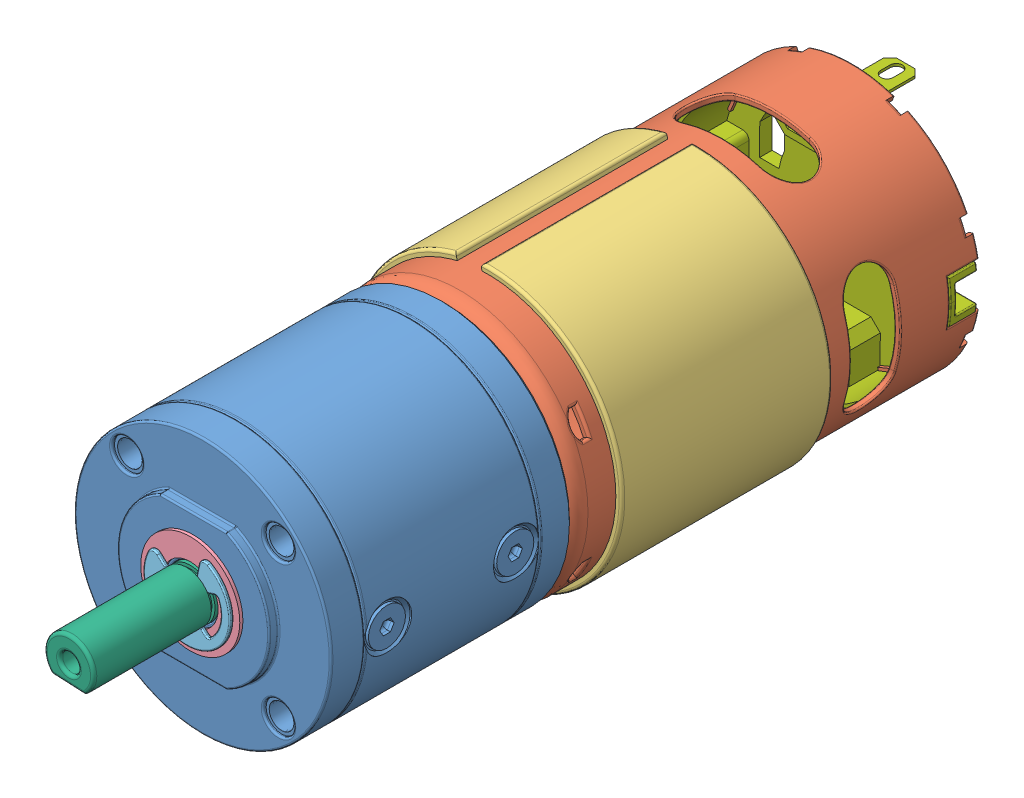
SolidWorks assembly motorDC, configuration Default. Lengths in mm.
Overall size (45.36 45.35 135.13).
7 component instances, 7 part files, 13 mates.
Components (placement in the parent):
- GearBox_motorDC-1: GearBox_motorDC [Default] at (0.9283 5.651 -4.329) size (41.59 41.5 40.5)
- Coil_motorDC-1: Coil_motorDC [Default] at (0.9283 5.651 -70.329) size (41.5 41.5 66.03)
- Gelung_motorDC-2: Gelung_motorDC [Default] at (0.9283 5.651 -45.329) x (0.999049 0.043602 0) z (0 0 1) size (43.5 43.5 34.08)
- Wessel_motorDC-1: Wessel_motorDC [Default] at (0.9283 5.651 36.171) x (0.331757 0.943365 0) z (0 0 1) size (16 16 0.5)
- Lock_motorDC-1: Lock_motorDC [Default] at (0.9283 5.651 36.671) x (-0.996748 0.080577 0) z (0 0 1) size (14 13.45 0.63)
- Shaft_motorDC-1: Shaft_motorDC [Default] at (0.9283 5.651 56.271) x (0.998745 -0.050076 0) z (0 0 -1) size (8 8 25.03)
- Brush_motorDC-1: Brush_motorDC [Default] at (0.9283 5.651 -69.329) x (-0.002572 -0.999997 0) z (0 0 1) size (39.5 41.5 19.5)
Mates (geometry in assembly coordinates):
- Coincident1: coincident: plane of GearBox_motorDC-1 through (0.9283 5.651 -4.329) normal (0 0 -1); plane of Coil_motorDC-1 through (0.9283 5.651 -4.329) normal (0 0 1)
- Concentric2: concentric: cylinder of GearBox_motorDC-1 through (0.9283 5.651 34.671) axis (0 0 -1) radius 17.75; cylinder of Coil_motorDC-1 through (0.9283 5.651 -70.33) axis (0 0 1) radius 15
- Concentric3: concentric: cylinder of Coil_motorDC-1 through (0.9283 5.651 -4.329) axis (0 0 -1) radius 20.75; cylinder of Gelung_motorDC-2 through (0.9283 5.651 -11.329) axis (0 0 -1) radius 20.75
- Distance1: distance = 25 mm: plane of Coil_motorDC-1 through (0.9283 5.651 -70.329) normal (0 0 -1); plane of Gelung_motorDC-2 through (0.9283 5.651 -45.329) normal (0 0 -1)
- Coincident2: coincident: plane of GearBox_motorDC-1 through (0.9283 5.651 36.171) normal (0 0 1); plane of Wessel_motorDC-1 through (0.9283 5.651 36.171) normal (0 0 -1)
- Concentric4: concentric: cylinder of GearBox_motorDC-1 through (0.9283 5.651 -4.329) axis (0 0 1) radius 4; cylinder of Wessel_motorDC-1 through (0.9283 5.651 36.671) axis (0 0 -1) radius 4.5
- Concentric5: concentric: cylinder of GearBox_motorDC-1 through (0.9283 5.651 -4.329) axis (0 0 1) radius 4; cylinder of Lock_motorDC-1 through (0.9283 5.651 37.271) axis (0 0 -1) radius 3.5
- Coincident3: coincident: plane of Wessel_motorDC-1 through (0.9283 5.651 36.671) normal (0 0 1); plane of Lock_motorDC-1 through (-4.4101 8.3898 36.671) normal (0 0 -1)
- Concentric6: concentric: cylinder of GearBox_motorDC-1 through (0.9283 5.651 -4.329) axis (0 0 1) radius 4; cylinder of Shaft_motorDC-1 through (0.9283 5.651 31.271) axis (0 0 1) radius 4
- Coincident4: coincident: plane of Lock_motorDC-1 through (-4.4101 8.3898 37.271) normal (0 0 1); plane of Shaft_motorDC-1 through (0.728 1.656 37.271) normal (0 0 -1)
- Concentric9: concentric: cylinder of Coil_motorDC-1 through (0.9283 5.651 -4.329) axis (0 0 -1) radius 19.75; cylinder of Brush_motorDC-1 through (0.9283 5.651 -59.329) axis (0 0 -1) radius 19.75
- Coincident7: coincident: plane of Coil_motorDC-1 through (21.6783 2.151 -65.329) normal (0 0 -1); plane of Brush_motorDC-1 through (17.2207 2.6591 -65.329) normal (0 0 1)
- Coincident9: coincident: line of Coil_motorDC-1 through (-18.5091 9.151 -70.329) axis (0 0 1); plane of Brush_motorDC-1 through (-15.3628 9.1429 -69.829) normal (0.002572 0.999997 0)
